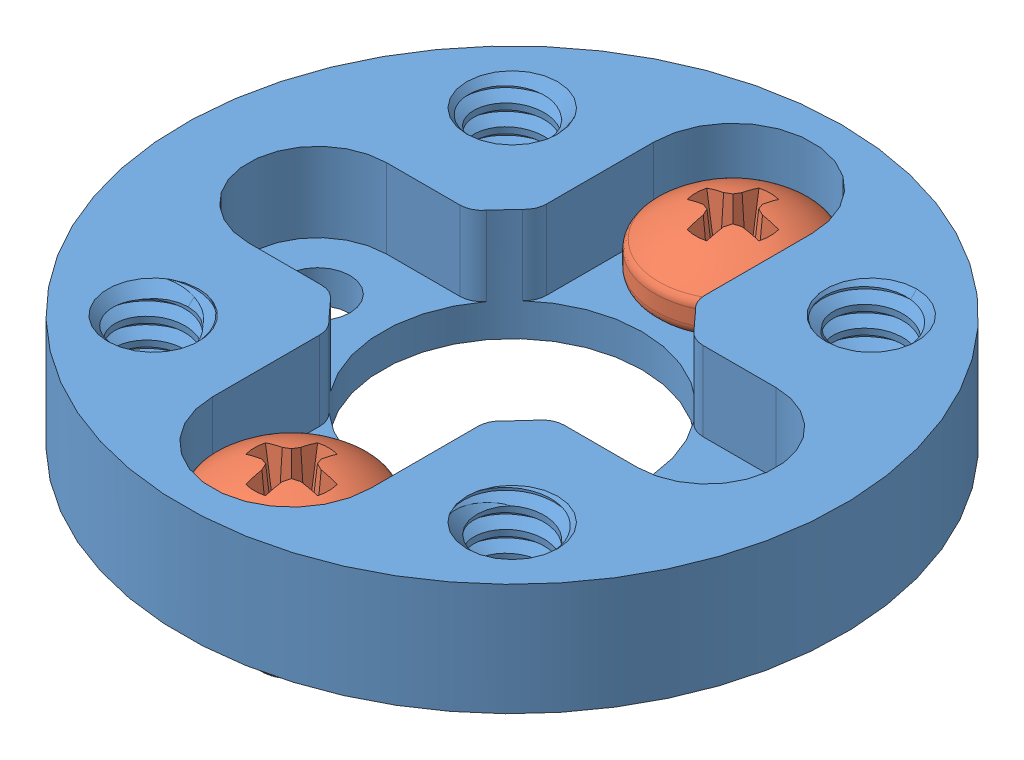
SolidWorks assembly Motor mount f, configuration Default. Lengths in mm.
Overall size (25.4 7.22 25.4).
5 component instances, 3 part files, 0 mates.
Components (placement in the parent):
- 555104-1: 555104 [Default] at (-70.4575 22.2385 20.6041) size (25.4 4.54 25.4)
- 555104 screw (M2.6)_92005A056-1: 555104 screw (M2.6)_92005A056 [Default] at (-77.9575 19.5085 20.6041) x (1 0 0) z (0 1 0) (suppressed, hidden)
- 555104 screw (M2.6)_92005A056-2: 555104 screw (M2.6)_92005A056 [Default] at (-62.9575 19.5085 20.6041) x (1 0 0) z (0 1 0) (suppressed, hidden)
- 555104 screw (M3)_92005A112-1: 555104 screw (M3)_92005A112 [Default] at (-70.4575 19.5085 12.1041) x (1 0 0) z (0 1 0) size (6 6 6.48)
- 555104 screw (M3)_92005A112-2: 555104 screw (M3)_92005A112 [Default] at (-70.4575 19.5085 29.1041) x (1 0 0) z (0 1 0) size (6 6 6.48)
